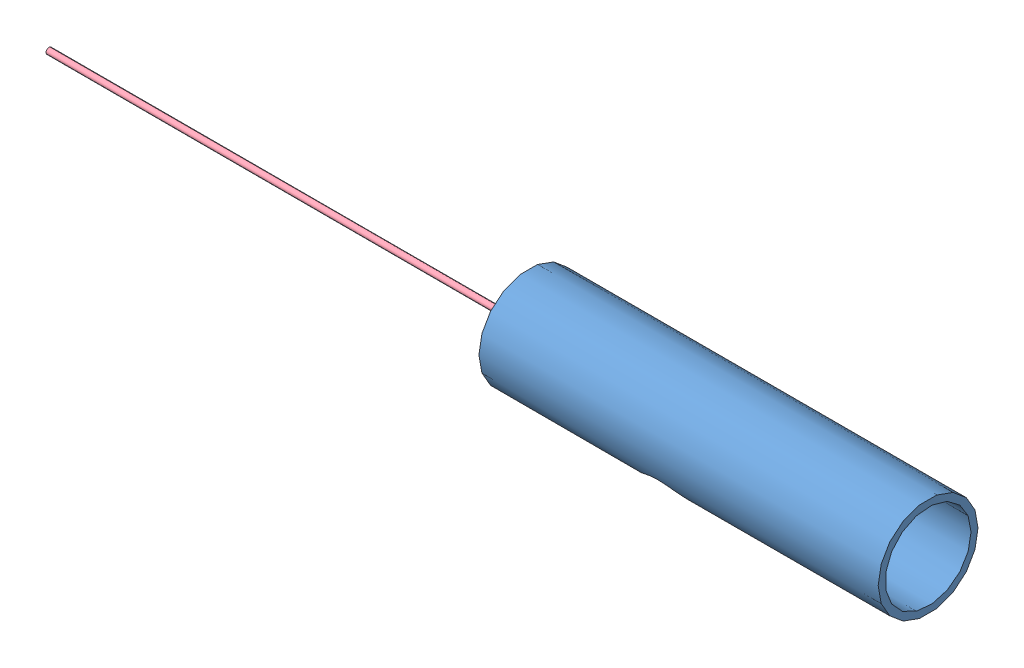
SolidWorks assembly compressed, configuration Default. Lengths in mm.
Overall size (440 50 50).
4 component instances, 4 part files, 6 mates.
Components (placement in the parent):
- tube-1: tube [Default] at origin size (200 50 50)
- compressed string-2: compressed string [Default] at (10 0 0) x (0 0 -1) z (0 -1 0) size (35.12 54.99 35.12)
- front plate-2: front plate [Default] at (60 -0.3273 0.3397) size (5 30 30)
- backplate-1: backplate [Default] at (-240 -0.3273 0.3397) size (300 3 3)
Mates (geometry in assembly coordinates):
- Coincident8: coincident anti-aligned: plane of tube-1 through (0 0 0) normal (0 1 0); plane of compressed string-2 through (10 0 0) normal (0 -1 0)
- Coincident10: coincident anti-aligned: plane of tube-1 through (0 0 0) normal (0 0 1); plane of compressed string-2
- Distance2: distance = 50 mm anti-aligned: plane of tube-1 through (10 0 0) normal (1 0 0); plane of front plate-2 through (60 -0.3273 0.3397) normal (-1 0 0)
- Distance4: distance = 10 mm: point of assembly; point of compressed string-2
- Coincident11: coincident anti-aligned: plane of front plate-2 through (60 -0.3273 0.3397) normal (-1 0 0); plane of backplate-1 through (60 -0.3273 0.3397) normal (1 0 0)
- Distance5: distance = 300 mm: point of backplate-1; point of front plate-2
